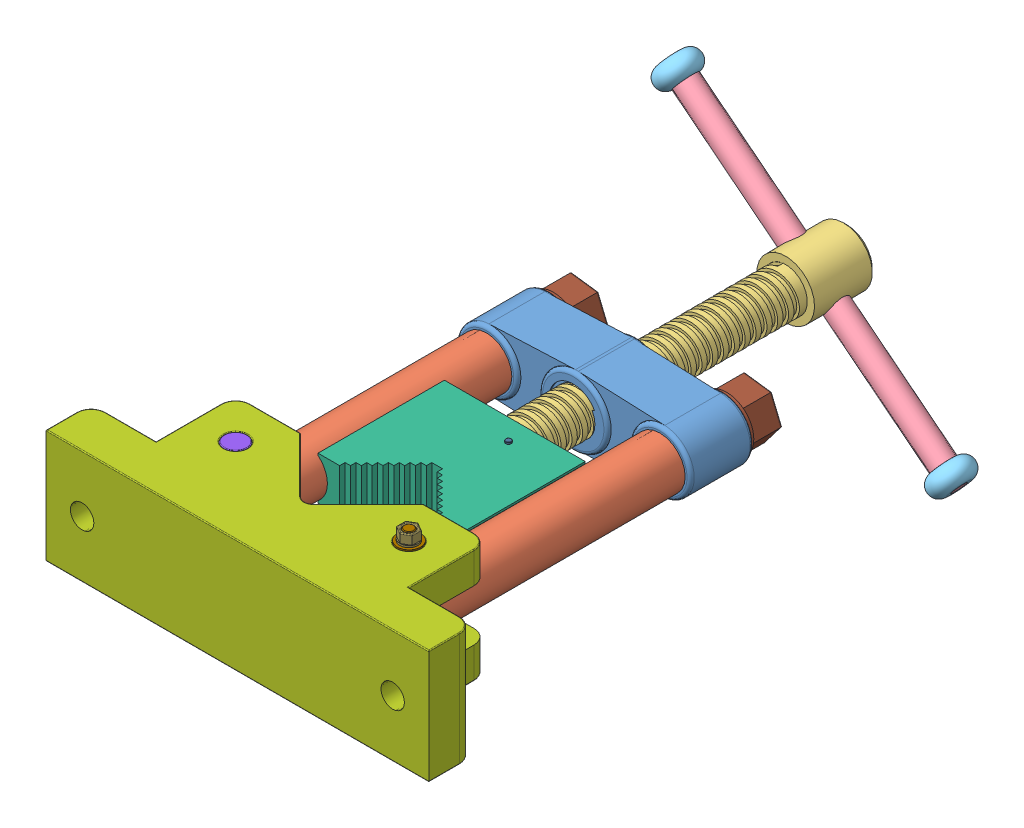
SolidWorks assembly Assem1, configuration Default. Lengths in mm.
Overall size (212 148.33 337.64).
15 component instances, 12 part files, 31 mates.
Components (placement in the parent):
- connecting wedge-1: connecting wedge [Default] at origin size (130 38 41.45)
- mounding shaft-1: mounding shaft [Default] at (-48 0 178.5) x (0 0 -1) z (0 1 0) size (216 28 28)
- mounding shaft-2: mounding shaft [Default] at (48 0 178.5) x (0 0 -1) z (0 -1 0) size (216 28 28)
- spindle screw-1: spindle screw [Default] at (0 0 -134.1446) x (0 0 1) z (-0.784305 0.620376 0) size (214 32 32)
- turning shaft-1: turning shaft [Default] at (79.9991 -63.2783 -116.1446) x (-0.784305 0.620376 0) z (0.158551 0.200447 0.96679) size (204 13 13)
- knob-1: knob [Default] at (79.9991 -63.2783 -116.1446) x (-0.784305 0.620376 0) z (-0.427216 -0.540104 0.725103) size (11 23 23)
- knob-2: knob [Default] at (-71.3717 56.4542 -116.1446) x (-0.784305 0.620376 0) z (0 0 1) size (11 23 23)
- movable jaws-2: movable jaws [Default] at (-39 0 49.8554) x (1 0 0) z (0 -1 0) size (78 70 24)
- fixed jaw-2: fixed jaw [Default] at (-106 0 203.5) x (1 0 0) z (0 1 0) size (212 69 63)
- mounding pin-1: mounding pin [Default] at (-48 -31.5 156.5) x (1 0 0) z (0 1 0) size (13 13 63)
- moving pin-1: moving pin [Default] at (48 -67.5 156.5) x (0 1 0) z (-0.807086 0 -0.590434) size (105.5 25 25)
- 3mm pin-1: 3mm pin [Default] at (8.5 -13 61.8554) x (1 0 0) z (0 1 0) size (3 3 26)
- nut-1: nut [Default] at (48 0 -17.5) x (-0.923728 -0.383049 0) z (0 0 -1) size (30 30 18)
- nut-2: nut [Default] at (-48 0 -17.5) x (-0.923728 -0.383049 0) z (0 0 -1) size (30 30 18)
- nut 2-1: nut 2 [Default] at (48 32 156.5) x (1 0 0) z (0 1 0) size (10 10 6)
Mates (geometry in assembly coordinates):
- Concentric1: concentric anti-aligned: cylinder of connecting wedge-1 through (-48 0 -17.5) axis (0 0 1) radius 11; cylinder of mounding shaft-1 through (-48 0 -37.5) axis (0 0 -1) radius 10
- Concentric2: concentric anti-aligned: cylinder of connecting wedge-1 through (48 0 -17.5) axis (0 0 1) radius 11; cylinder of mounding shaft-2 through (48 0 -37.5) axis (0 0 -1) radius 10
- Coincident1: coincident anti-aligned: plane of connecting wedge-1 through (0 0 17.5) normal (0 0 1); plane of mounding shaft-2 through (58 0 17.5) normal (0 0 -1)
- Coincident2: coincident anti-aligned: plane of connecting wedge-1 through (0 0 17.5) normal (0 0 1); plane of mounding shaft-1 through (-58 0 17.5) normal (0 0 -1)
- Concentric3: concentric anti-aligned: cylinder of connecting wedge-1 through (0 0 17.5) axis (0 0 1) radius 12; cylinder of spindle screw-1 through (0 0 -134.1446) axis (0 0 -1) radius 12
- Coincident3: coincident aligned: plane of turning shaft-1 through (-79.9991 63.2783 -116.1446) normal (-0.784305 0.620376 0); plane of knob-2 through (-83.7213 58.5725 -116.1446) normal (-0.784305 0.620376 0)
- Concentric4: concentric anti-aligned: cylinder of turning shaft-1 through (79.9991 -63.2783 -116.1446) axis (0.784305 -0.620376 0) radius 4; cylinder of knob-2 through (-135.2084 106.9482 -116.1446) axis (-0.784305 0.620376 0) radius 4.05
- Concentric5: concentric anti-aligned: cylinder of turning shaft-1 through (79.9991 -63.2783 -116.1446) axis (0.784305 -0.620376 0) radius 4; cylinder of knob-1 through (16.1624 -12.7843 -116.1446) axis (-0.784305 0.620376 0) radius 4.05
- Coincident4: coincident aligned: plane of turning shaft-1 through (77.6 -66.3114 -115.1223) normal (0.784305 -0.620376 0); plane of knob-1 through (78.1773 -65.5816 -118.9336) normal (0.784305 -0.620376 0)
- Concentric6: concentric anti-aligned: cylinder of spindle screw-1 through (19.6076 -15.5094 -116.1446) axis (-0.784305 0.620376 0) radius 6.5; cylinder of turning shaft-1 through (79.9991 -63.2783 -116.1446) axis (0.784305 -0.620376 0) radius 6.5
- Distance1: distance = 102 mm anti-aligned: plane of spindle screw-1 through (0 0 -134.1446) normal (-0.784305 0.620376 0); plane of knob-1 through (78.1773 -65.5816 -118.9336) normal (0.784305 -0.620376 0)
- Screw1: screw = 1 mm anti-aligned: cylinder of connecting wedge-1 through (0 0 17.5) axis (0 0 1) radius 12; cylinder of spindle screw-1 through (0 0 -134.1446) axis (0 0 -1) radius 12
- Concentric17: concentric aligned: cylinder of spindle screw-1 through (0 0 -134.1446) axis (0 0 -1) radius 8.5; cylinder of movable jaws-2 through (0 0 49.8554) axis (0 0 -1) radius 8.5
- Parallel4: parallel aligned: plane of connecting wedge-1 through (0 0 0) normal (0 1 0); plane of movable jaws-2 through (-39 12 49.8554) normal (0 1 0)
- Coincident10: coincident anti-aligned: plane of spindle screw-1 through (5.2732 6.6666 49.8554) normal (0 0 1); plane of movable jaws-2 through (-39 -12 49.8554) normal (0 0 -1)
- Parallel5: parallel aligned: plane of movable jaws-2 through (-39 12 49.8554) normal (0 1 0); plane of fixed jaw-2 through (98 31.5 186.5) normal (0 1 0)
- Concentric18: concentric anti-aligned: cylinder of mounding shaft-2 through (48 25 156.5) axis (0 -1 0) radius 6.525; cylinder of fixed jaw-2 through (48 -31.5 156.5) axis (0 1 0) radius 6.5
- Width2: width aligned: plane of fixed jaw-2 through (98 31.5 186.5) normal (0 1 0); plane of fixed jaw-2 through (98 -31.5 186.5) normal (0 -1 0); plane of movable jaws-2 through (-39 12 49.8554) normal (0 1 0); plane of movable jaws-2 through (-39 -12 49.8554) normal (0 -1 0)
- LimitDistance2: limit distance = 32.3554 mm anti-aligned: plane of movable jaws-2 through (-39 -12 49.8554) normal (0 0 -1); plane of connecting wedge-1 through (0 0 17.5) normal (0 0 1)
- Concentric19: concentric anti-aligned: cylinder of fixed jaw-2 through (-48 -31.5 156.5) axis (0 1 0) radius 6.5; cylinder of mounding pin-1 through (-48 31.5 156.5) axis (0 -1 0) radius 6.5
- Coincident12: coincident aligned: plane of fixed jaw-2 through (98 -31.5 186.5) normal (0 -1 0); plane of mounding pin-1 through (-48 -31.5 156.5) normal (0 -1 0)
- Concentric20: concentric anti-aligned: cylinder of fixed jaw-2 through (48 -31.5 156.5) axis (0 1 0) radius 6.5; cylinder of moving pin-1 through (48 -67.5 156.5) axis (0 -1 0) radius 6.5
- Coincident13: coincident anti-aligned: plane of fixed jaw-2 through (98 -31.5 186.5) normal (0 -1 0); plane of moving pin-1 through (51.8378 -31.5 151.2539) normal (0 1 0)
- Concentric21: concentric anti-aligned: cylinder of movable jaws-2 through (8.5 12 61.8554) axis (0 1 0) radius 1.5; cylinder of 3mm pin-1 through (8.5 13 61.8554) axis (0 -1 0) radius 1.5
- Width3: width aligned: plane of movable jaws-2 through (-39 -12 49.8554) normal (0 -1 0); plane of movable jaws-2 through (-39 12 49.8554) normal (0 1 0); plane of 3mm pin-1 through (8.5 -13 61.8554) normal (0 -1 0); plane of 3mm pin-1 through (8.5 13 61.8554) normal (0 1 0)
- Concentric23: concentric anti-aligned: cylinder of mounding shaft-2 through (48 0 -37.5) axis (0 0 -1) radius 8; cylinder of nut-1 through (48 0 -35.5) axis (0 0 1) radius 8
- Coincident14: coincident anti-aligned: plane of connecting wedge-1 through (0 0 -17.5) normal (0 0 -1); plane of nut-1 through (48 0 -17.5) normal (0 0 1)
- Concentric24: concentric anti-aligned: cylinder of mounding shaft-1 through (-48 0 -37.5) axis (0 0 -1) radius 8; cylinder of nut-2 through (-48 0 -35.5) axis (0 0 1) radius 8
- Coincident15: coincident anti-aligned: plane of connecting wedge-1 through (0 0 -17.5) normal (0 0 -1); plane of nut-2 through (-48 0 -17.5) normal (0 0 1)
- Concentric25: concentric aligned: cylinder of moving pin-1 through (48 -67.5 156.5) axis (0 -1 0) radius 3; cylinder of nut 2-1 through (48 38 156.5) axis (0 -1 0) radius 3
- Coincident16: coincident anti-aligned: plane of moving pin-1 through (49.7713 32 154.0787) normal (0 1 0); plane of nut 2-1 through (48 32 156.5) normal (0 -1 0)
